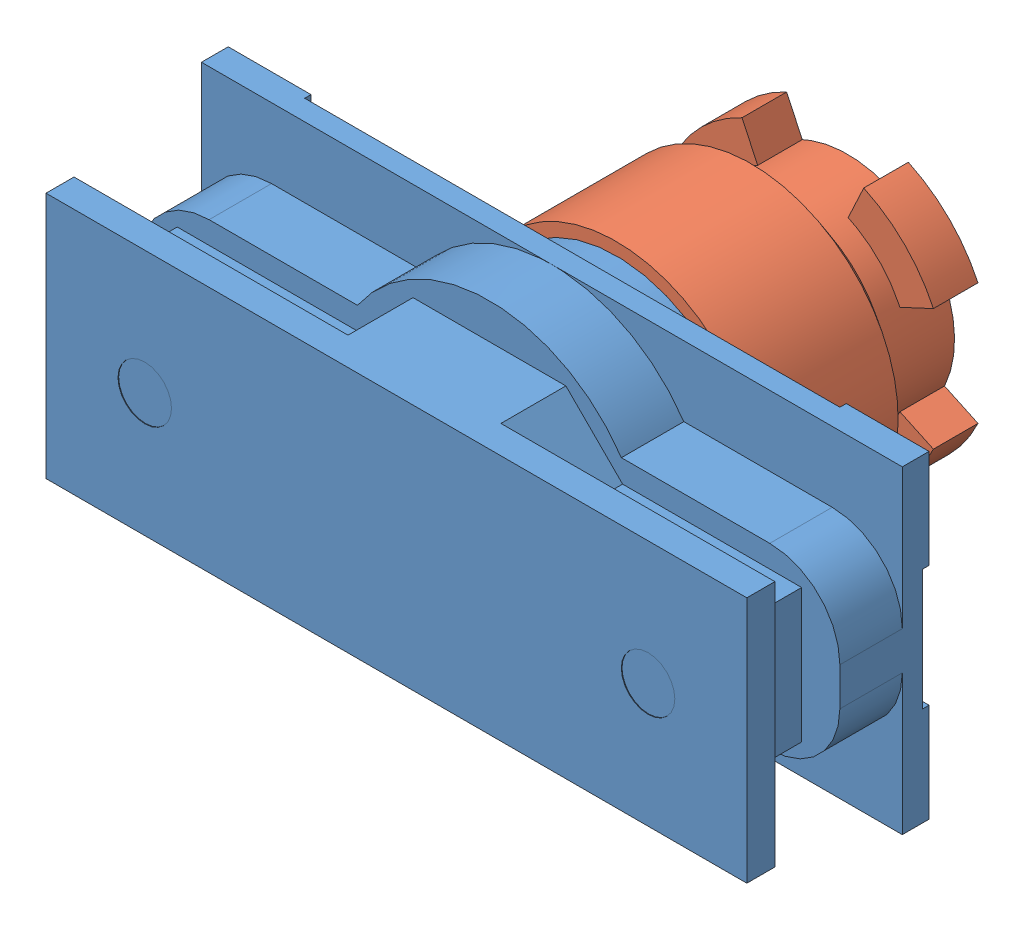
SolidWorks assembly PUTM-H-TS-BOX-HVD, configuration Domyślna. Lengths in mm.
Overall size (110 65.34 70.8).
2 component instances, 2 part files, 3 mates.
Components (placement in the parent):
- PUTM-H-TS-BOX-HVDa-1: PUTM-H-TS-BOX-HVDa [Domyślna] at (-15.6903 3.7815 110) size (110 50 34.5)
- PUTM-H-TS-BOX-HVDb-1: PUTM-H-TS-BOX-HVDb [Domyślna] at (-15.6903 3.7815 104.1) x (0.707107 -0.707107 0) z (0.707107 0.707107 0) size (46.2 36.3 46.2)
Mates (geometry in assembly coordinates):
- Wspólnie1: coincident anti-aligned: plane of PUTM-H-BT-BB-HVDa-1 through (-15.6903 3.7815 104.1) normal (0 0 -1); plane of PUTM-H-BT-BB-HVDb-1 through (-15.6903 3.7815 104.1) normal (0 0 1)
- Koncentryczne1: concentric anti-aligned: cylinder of PUTM-H-BT-BB-HVDa-1 through (-15.6903 3.7815 104.1) axis (0 0 1) radius 21.15; cylinder of PUTM-H-BT-BB-HVDb-1 through (-15.6903 3.7815 81.8) axis (0 0 -1) radius 23.1
- Równolegle1: parallel: plane of PUTM-H-BT-BB-HVDa-1 through (-70.6903 -21.2185 114.2) normal (-1 0 0); line of PUTM-H-BT-BB-HVDb-1 through (-15.6903 3.7815 67.8) axis (0 -1 0)
